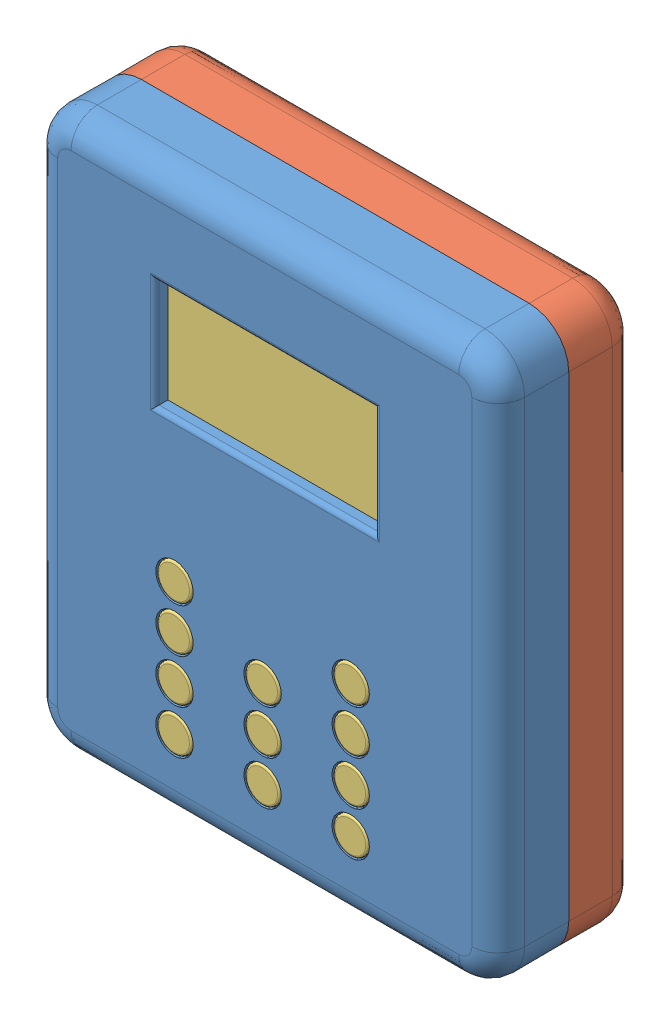
SolidWorks assembly Assem1, configuration Default. Lengths in mm.
Overall size (106 126 31.97).
4 component instances, 3 part files, 7 mates.
Components (placement in the parent):
- EnclousureTop-1: EnclousureTop [Default] at origin size (106 126 16)
- EnclousureBottom-3: EnclousureBottom [Default] at (100 0 26.1252) x (-1 0 0) z (0 0 -1) size (106 126 15.87)
- Part3-1: Part3 [Default] at (0 0 24.1) size (61.12 59.63 5)
- Part3-2: Part3 [Default] at (96.1152 55.911 26) x (-1 0 0) z (0 0 -1) size (61.12 59.63 5)
Mates (geometry in assembly coordinates):
- Coincident2: coincident anti-aligned: plane of EnclousureTop-1 through (119.2323 130 12.9988) normal (0 0 -1); plane of EnclousureBottom-3 through (108.553 141.7258 12.9988) normal (0 0 1)
- Coincident3: coincident: point of EnclousureTop-1; point of EnclousureBottom-3
- Concentric1: concentric anti-aligned: cylinder of EnclousureTop-1 through (49.5 14 12.9988) axis (0 0 1) radius 4.25; circle of Part3-1
- Concentric2: concentric aligned: circle of EnclousureTop-1; circle of Part3-1
- Distance2: distance = 0.1 mm anti-aligned: plane of EnclousureTop-1 through (6 6 26) normal (0 0 -1); plane of Part3-1 through (0 0 26.1) normal (0 0 1)
- Coincident4: coincident anti-aligned: plane of EnclousureTop-1 through (6 6 26) normal (0 0 -1); plane of Part3-2 through (96.1152 55.911 26) normal (0 0 1)
- Parallel4: parallel anti-aligned: line of EnclousureTop-1 through (6 0 12.9988) axis (1 0 0); line of Part3-2 through (78.8131 55.911 24) axis (-1 0 0)
